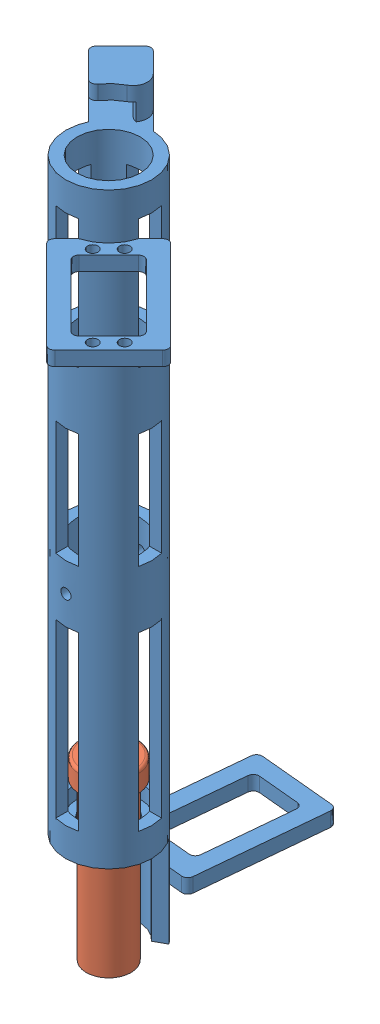
SolidWorks assembly plungerassembly, configuration Default. Lengths in mm.
Overall size (98.43 322.58 144.99).
2 component instances, 2 part files, 2 mates.
Components (placement in the parent):
- NerfGunTube-1: NerfGunTube [Default] at (306.1385 373.954 -53.7492) size (98.43 314.96 144.99)
- PlungerAttempt-1: PlungerAttempt [Default] at (306.1385 395.544 -53.7492) x (-0.008872 0 -0.999961) z (0.999961 0 -0.008872) size (25.4 78.74 25.4)
Mates (geometry in assembly coordinates):
- Concentric1: concentric anti-aligned: circle of NerfGunTube-1; circle of PlungerAttempt-1
- Distance1: distance = 15.24 mm anti-aligned: plane of NerfGunTube-1 through (306.1385 380.304 -53.7492) normal (0 1 0); plane of PlungerAttempt-1 through (306.1385 395.544 -53.7492) normal (0 -1 0)
